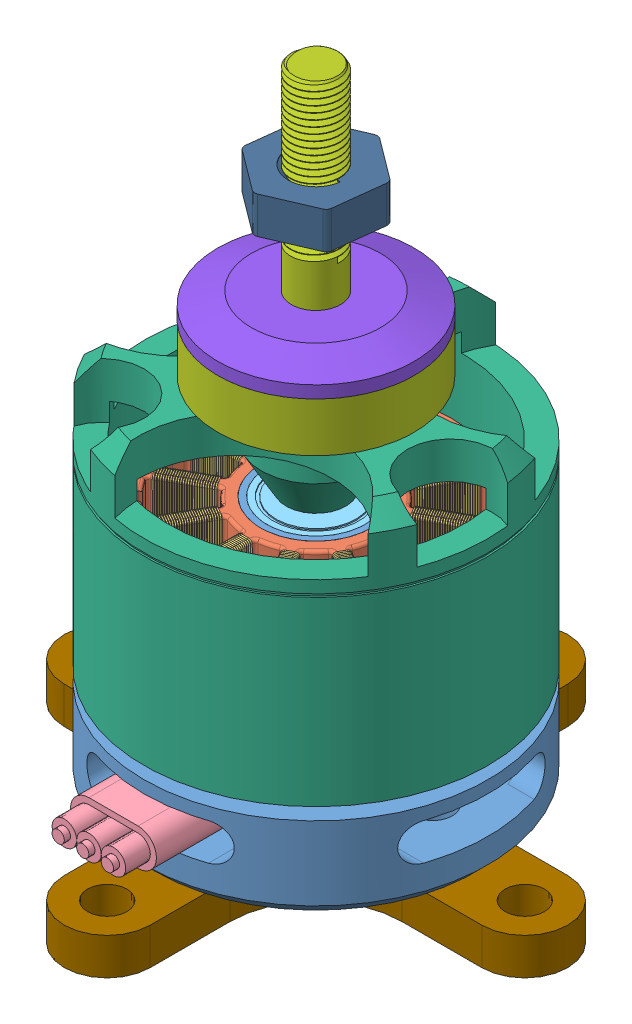
SolidWorks assembly Motor_wo_Prop, configuration Default. Lengths in mm.
Overall size (41 53.8 41).
22 component instances, 10 part files, 28 mates.
Components (placement in the parent):
- Housing_Bottom-1: Housing_Bottom [Default] at origin size (28 20 28)
- Stator-1: Stator [Default] at (0 8 0) size (22 12.2 22)
  - Stator_Steelcore-1: Stator_Steelcore [Default] at origin size (22 12.05 22)
  - Stator_Coil-1: Stator_Coil [Default] at (-2.8504 6 4.9371) x (0.5 0 -0.866025) z (0.866025 0 0.5) size (4.11 12.2 1.21)
  - Stator_Coil-2: Stator_Coil [Default] at (0 6 5.7009) x (0 0 -1) z (1 0 0) size (4.11 12.2 1.21)
  - Stator_Coil-3: Stator_Coil [Default] at (2.8504 6 4.9371) x (-0.5 0 -0.866025) z (0.866025 0 -0.5) size (4.11 12.2 1.21)
  - Stator_Coil-4: Stator_Coil [Default] at (4.9371 6 2.8504) x (-0.866025 0 -0.5) z (0.5 0 -0.866025) size (4.11 12.2 1.21)
  - Stator_Coil-5: Stator_Coil [Default] at (5.7009 6 0) x (-1 0 0) z (0 0 -1) size (4.11 12.2 1.21)
  - Stator_Coil-6: Stator_Coil [Default] at (4.9371 6 -2.8504) x (-0.866025 0 0.5) z (-0.5 0 -0.866025) size (4.11 12.2 1.21)
  - Stator_Coil-7: Stator_Coil [Default] at (2.8504 6 -4.9371) x (-0.5 0 0.866025) z (-0.866025 0 -0.5) size (4.11 12.2 1.21)
  - Stator_Coil-8: Stator_Coil [Default] at (0 6 -5.7009) x (0 0 1) z (-1 0 0) size (4.11 12.2 1.21)
  - Stator_Coil-9: Stator_Coil [Default] at (-2.8504 6 -4.9371) x (0.5 0 0.866025) z (-0.866025 0 0.5) size (4.11 12.2 1.21)
  - Stator_Coil-10: Stator_Coil [Default] at (-4.9371 6 -2.8504) x (0.866025 0 0.5) z (-0.5 0 0.866025) size (4.11 12.2 1.21)
  - Stator_Coil-11: Stator_Coil [Default] at (-5.7009 6 0) size (4.11 12.2 1.21)
  - Stator_Coil-12: Stator_Coil [Default] at (-4.9371 6 2.8504) x (0.866025 0 -0.5) z (0.5 0 0.866025) size (4.11 12.2 1.21)
- Wiring-1: Wiring [Default] at (0.0116 4.5 16.5) x (1 0 0) z (0 0 -1) size (7 3 14.5)
- Rotor-1: Rotor [Default] x (-0.598049 0 0.80146) z (-0.80146 0 -0.598049) size (8 31.7 8)
- Housing_Upper-1: Housing_Upper [Default] at (0 8 0) x (-0.598049 0 0.80146) z (-0.80146 0 -0.598049) size (28 22 28)
- CapScrew-1: CapScrew [Default] at (0 28.5 0) x (0.117196 0 -0.993109) z (0.993109 0 0.117196) size (16 22.3 16)
- Cap-1: Cap [Default] at (0 32.5 0) x (0.117196 0 -0.993109) z (0.993109 0 0.117196) size (16 2 16)
- CrossBase-1: CrossBase [Default] at (0 -3 0) size (41 3 41)
- Nut-1: Nut [Default] at (0 40.4 0) x (0.117196 0 -0.993109) z (0.993109 0 0.117196) size (9.08 3.45 8)
Mates (geometry in assembly coordinates):
- Concentric1: concentric aligned: cylinder of Stator-1/Stator_Steelcore-1 through (0 20 0) axis (0 -1 0) radius 4.5; cylinder of Housing_Bottom-1 through (0 20 0) axis (0 -1 0) radius 4.5
- Coincident1: coincident aligned: plane of Housing_Bottom-1 through (0 20 0) normal (0 1 0); plane of Stator-1/Stator_Steelcore-1 through (0 20 0) normal (0 1 0)
- Coincident2: coincident anti-aligned: plane of Housing_Bottom-1 through (0 3 0) normal (0 1 0); plane of Wiring-1 through (-1.9884 3 6.5) normal (0 -1 0)
- Lock1: lock: unknown of Housing_Bottom-1; unknown of Wiring-1
- Tangent1: tangent anti-aligned: cylinder of Housing_Bottom-1 through (0 20 0) axis (0 -1 0) radius 4.5; plane of Wiring-1 through (0.0116 4.5 4.5) normal (0 0 -1)
- Coincident6: coincident aligned: plane of Housing_Bottom-1 through (0 20 0) normal (0 1 0); plane of Rotor-1 through (0 20 0) normal (0 1 0)
- Concentric2: concentric aligned: cylinder of Housing_Bottom-1 through (0 14.3137 0) axis (0 -1 0) radius 4; cylinder of Rotor-1 through (0 20 0) axis (0 -1 0) radius 4
- Concentric3: concentric anti-aligned: cylinder of Rotor-1 through (0 30 0) axis (0 -1 0) radius 1.5; cylinder of Housing_Upper-1 through (0 8 0) axis (0 1 0) radius 1.5
- Distance1: distance = 8 mm aligned: plane of Housing_Upper-1; plane of Housing_Bottom-1 through (0 0 0) normal (0 1 0)
- Coincident10: coincident aligned: plane of Housing_Bottom-1 through (0 0 0) normal (0 0 1); plane of Stator-1/Stator_Steelcore-1 through (0 8 0) normal (0 0 1)
- Coincident11: coincident aligned: plane of Rotor-1 through (0 0 0) normal (-0.80146 0 -0.598049); plane of Housing_Upper-1 through (0 8 0) normal (-0.80146 0 -0.598049)
- Coincident12: coincident aligned: plane of Housing_Bottom-1 through (0 0 0) normal (0 0 1); plane of assembly through (0 0 0) normal (0 0 1)
- Coincident13: coincident aligned: plane of Housing_Bottom-1 through (0 0 0) normal (0 1 0); plane of assembly through (0 0 0) normal (0 1 0)
- Coincident14: coincident aligned: plane of Housing_Bottom-1 through (0 0 0) normal (1 0 0); plane of assembly through (0 0 0) normal (1 0 0)
- Concentric4: concentric anti-aligned: cylinder of Housing_Upper-1 through (0 9.9135 0) axis (0 1 0) radius 4.45; cylinder of CapScrew-1 through (0 30 0) axis (0 -1 0) radius 4.5
- Concentric5: concentric aligned: cylinder of Housing_Upper-1 through (-2.3704 28.5 -5.5119) axis (0 1 0) radius 0.625; cylinder of CapScrew-1 through (-2.3704 32.5 -5.5119) axis (0 1 0) radius 0.85
- Concentric6: concentric aligned: cylinder of Housing_Upper-1 through (5.9587 28.5 0.7032) axis (0 1 0) radius 0.625; cylinder of CapScrew-1 through (5.9587 32.5 0.7032) axis (0 1 0) radius 0.85
- Concentric7: concentric aligned: cylinder of Housing_Upper-1 through (-3.5883 28.5 4.8088) axis (0 1 0) radius 0.625; cylinder of CapScrew-1 through (-3.5883 32.5 4.8088) axis (0 1 0) radius 0.85
- Coincident15: coincident anti-aligned: plane of Housing_Upper-1 through (0 28.5 0) normal (0 1 0); plane of CapScrew-1 through (0 28.5 0) normal (0 -1 0)
- Concentric8: concentric anti-aligned: cylinder of CapScrew-1 through (0 50.5 0) axis (0 -1 0) radius 2; cylinder of Cap-1 through (0 32.5 0) axis (0 1 0) radius 2
- Coincident16: coincident anti-aligned: plane of CapScrew-1 through (0 32.5 0) normal (0 1 0); plane of Cap-1 through (0 32.5 0) normal (0 -1 0)
- Concentric19: concentric aligned: cylinder of Housing_Bottom-1 through (0 0 8) axis (0 -1 0) radius 1.6; cylinder of CrossBase-1 through (0 -3 8) axis (0 -1 0) radius 1.6
- Concentric21: concentric aligned: cylinder of Housing_Bottom-1 through (0 0 -8) axis (0 -1 0) radius 1.6; cylinder of CrossBase-1 through (0 -3 -8) axis (0 -1 0) radius 1.6
- Coincident18: coincident anti-aligned: plane of Housing_Bottom-1 through (0 0 0) normal (0 -1 0); plane of CrossBase-1 through (0 0 0) normal (0 1 0)
- Coincident19: coincident aligned: plane of CapScrew-1 through (0 28.5 0) normal (0.993109 0 0.117196); plane of Cap-1 through (0 32.5 0) normal (0.993109 0 0.117196)
- Concentric22: concentric anti-aligned: cylinder of CapScrew-1 through (0 50.5 0) axis (0 -1 0) radius 2; cylinder of Nut-1 through (0 40.4 0) axis (0 1 0) radius 2.25
- Parallel3: parallel aligned: plane of Cap-1 through (0 34.5 0) normal (0 1 0); plane of Nut-1 through (0 43.4 0) normal (0 1 0)
- Coincident26: coincident aligned: plane of Cap-1 through (0 32.5 0) normal (0.993109 0 0.117196); plane of Nut-1 through (0 40.4 0) normal (0.993109 0 0.117196)
